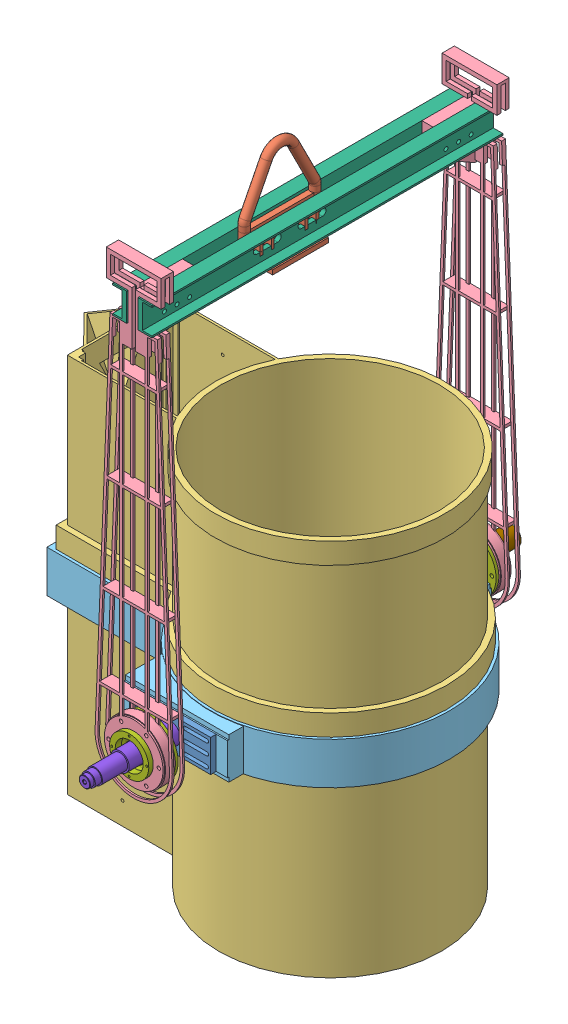
SolidWorks assembly MAIN ASSEMBLY, configuration Default. Lengths in mm.
Overall size (1306.1 2334 1530).
13 component instances, 9 part files, 32 mates.
Components (placement in the parent):
- END BRACKET ON TRUNNION SHAFT - GEAR END & OFF END-1: END BRACKET ON TRUNNION SHAFT - GEAR END & OFF END [Default] at (1445.5704 513.2068 -637.5435) x (1 0 0) z (0 -1 0) size (290 20 115)
- HOOK-1: HOOK [Default] at (1445.5704 1896.7068 -44.8635) x (0 0 -1) z (1 0 0) size (284 342 150)
- SHEEL-1: SHEEL [Default] at (1525.5704 -170.7932 -145.5435) size (1297.1 1360 836)
- SIDE BAILARM-1: SIDE BAILARM [Default] at (1445.5704 513.2068 -745.5435) size (276 1657 194)
- T.RING WITH BRACKETS-1: T.RING WITH BRACKETS [Default] at (1525.5704 438.2068 -145.5435) x (-1 0 0) z (0 0 -1) size (1226.08 150 944)
- TOP BAILARM-1: TOP BAILARM [Default] at (1417.5704 1887.2068 -772.5435) x (0 0 1) z (-1 0 0) size (1254 100 50)
- TRUNNION HOUSING - GEAR END, OFF END - FINISHING-1: TRUNNION HOUSING - GEAR END, OFF END - FINISHING [Default] at (1445.5704 513.2068 417.4565) x (1 0.000054 0) z (0.000054 -1 0) size (210 75 210)
- TRUNNION SHAFT - GEAR END-1: TRUNNION SHAFT - GEAR END [Default] at (1445.5704 513.2068 329.4565) x (0 0 1) z (0.352968 0.935635 0) size (323 75 75)
- TRUNNION SHAFT - OFF END-1: TRUNNION SHAFT - OFF END [Default] at (1445.5704 513.2068 -620.5435) x (0 0 -1) z (1 0 0) size (257 75 75)
- SIDE BAILARM-2: SIDE BAILARM [Default] at (1445.5704 513.2068 454.4565) x (-1 0 0) z (0 0 -1) size (276 1657 194)
- END BRACKET ON TRUNNION SHAFT - GEAR END & OFF END-2: END BRACKET ON TRUNNION SHAFT - GEAR END & OFF END [Default] at (1445.5704 513.2068 346.4565) x (-1 0 0) z (0 -1 0) size (290 20 115)
- TRUNNION HOUSING - GEAR END, OFF END - FINISHING-2: TRUNNION HOUSING - GEAR END, OFF END - FINISHING [Default] at (1445.5704 513.2068 -708.5435) x (1 0 0) z (0 1 0) size (210 75 210)
- TOP BAILARM-2: TOP BAILARM [Default] at (1473.5704 1887.2068 -772.5435) x (0 0 1) z (1 0 0) size (1254 100 50)
Mates (geometry in assembly coordinates):
- Concentric1: concentric aligned: cylinder of SHEEL-1 through (1525.5704 1189.2068 -145.5435) axis (0 -1 0) radius 398; cylinder of T.RING WITH BRACKETS-1 through (1525.5704 588.2068 -145.5435) axis (0 -1 0) radius 402
- Coincident1: coincident anti-aligned: plane of SHEEL-1 through (1525.5704 588.2068 -145.5435) normal (0 -1 0); plane of T.RING WITH BRACKETS-1 through (1525.5704 588.2068 -145.5435) normal (0 1 0)
- Coincident2: coincident anti-aligned: plane of END BRACKET ON TRUNNION SHAFT - GEAR END & OFF END-1 through (1445.5704 513.2068 -637.5435) normal (0 0 -1); plane of TRUNNION SHAFT - OFF END-1 through (1445.5704 527.9068 -637.5435) normal (0 0 1)
- Concentric2: concentric aligned: cylinder of END BRACKET ON TRUNNION SHAFT - GEAR END & OFF END-1 through (1445.5704 513.2068 -637.5435) axis (0 0 1) radius 14.75; cylinder of TRUNNION SHAFT - OFF END-1 through (1445.5704 513.2068 -620.5435) axis (0 0 1) radius 14.7
- Coincident3: coincident anti-aligned: plane of TRUNNION SHAFT - GEAR END-1 through (1459.3242 508.0182 346.4565) normal (0 0 -1); plane of END BRACKET ON TRUNNION SHAFT - GEAR END & OFF END-2 through (1445.5704 513.2068 346.4565) normal (0 0 1)
- Concentric3: concentric aligned: cylinder of TRUNNION SHAFT - GEAR END-1 through (1445.5704 513.2068 329.4565) axis (0 0 -1) radius 14.7; cylinder of END BRACKET ON TRUNNION SHAFT - GEAR END & OFF END-2 through (1445.5704 513.2068 346.4565) axis (0 0 -1) radius 14.75
- Coincident4: coincident anti-aligned: plane of END BRACKET ON TRUNNION SHAFT - GEAR END & OFF END-1 through (1445.5704 513.2068 -617.5435) normal (0 0 1); plane of T.RING WITH BRACKETS-1 through (1525.5704 438.2068 -617.5435) normal (0 0 -1)
- Coincident6: coincident aligned: plane of END BRACKET ON TRUNNION SHAFT - GEAR END & OFF END-1 through (1300.5704 570.7068 -617.5435) normal (0 1 0); plane of T.RING WITH BRACKETS-1 through (1630.5704 570.7068 -617.5435) normal (0 1 0)
- Width1: width anti-aligned: plane of T.RING WITH BRACKETS-1 through (1630.5704 439.7068 -612.5435) normal (1 0 0); plane of END BRACKET ON TRUNNION SHAFT - GEAR END & OFF END-1 through (1260.5704 439.7068 -612.5435) normal (-1 0 0); plane of T.RING WITH BRACKETS-1 through (1300.5704 455.7068 -617.5435) normal (-1 0 0); plane of END BRACKET ON TRUNNION SHAFT - GEAR END & OFF END-1 through (1590.5704 455.7068 -617.5435) normal (1 0 0)
- Coincident9: coincident anti-aligned: plane of SIDE BAILARM-1 through (1445.5704 513.2068 -723.5435) normal (0 0 1); plane of TRUNNION HOUSING - GEAR END, OFF END - FINISHING-2 through (1445.5704 513.2068 -723.5435) normal (0 0 -1)
- Concentric6: concentric aligned: cylinder of SIDE BAILARM-1 through (1445.5704 513.2068 -767.5435) axis (0 0 1) radius 70; cylinder of TRUNNION HOUSING - GEAR END, OFF END - FINISHING-2 through (1445.5704 513.2068 -783.5445) axis (0 0 1) radius 50
- Concentric7: concentric anti-aligned: cylinder of SIDE BAILARM-1 through (1535.5704 513.2068 -723.5435) axis (0 0 1) radius 6.25; cylinder of TRUNNION HOUSING - GEAR END, OFF END - FINISHING-2 through (1535.5704 513.2068 -723.5435) axis (0 0 -1) radius 6.5
- Concentric8: concentric aligned: cylinder of TRUNNION SHAFT - OFF END-1 through (1445.5704 513.2068 -620.5435) axis (0 0 1) radius 37.5; cylinder of TRUNNION HOUSING - GEAR END, OFF END - FINISHING-2 through (1445.5704 513.2068 -741.0435) axis (0 0 1) radius 55.4
- Width2: width aligned: plane of T.RING WITH BRACKETS-1 through (1630.5704 439.7068 -612.5435) normal (1 0 0); plane of SIDE BAILARM-1 through (1260.5704 439.7068 -612.5435) normal (-1 0 0); plane of T.RING WITH BRACKETS-1 through (1465.5704 513.2068 -745.5435) normal (1 0 0); plane of SIDE BAILARM-1 through (1425.5704 513.2068 -745.5435) normal (-1 0 0)
- Coincident10: coincident anti-aligned: plane of TRUNNION HOUSING - GEAR END, OFF END - FINISHING-1 through (1445.5704 513.2068 432.4565) normal (0 0 1); plane of SIDE BAILARM-2 through (1445.5704 513.2068 432.4565) normal (0 0 -1)
- Concentric9: concentric aligned: cylinder of TRUNNION HOUSING - GEAR END, OFF END - FINISHING-1 through (1445.5704 513.2068 492.4575) axis (0 0 -1) radius 70; cylinder of SIDE BAILARM-2 through (1445.5704 513.2068 476.4565) axis (0 0 -1) radius 70
- Coincident11: coincident anti-aligned: plane of T.RING WITH BRACKETS-1 through (1525.5704 438.2068 326.4565) normal (0 0 1); plane of END BRACKET ON TRUNNION SHAFT - GEAR END & OFF END-2 through (1445.5704 513.2068 326.4565) normal (0 0 -1)
- Coincident13: coincident aligned: plane of T.RING WITH BRACKETS-1 through (1630.5704 570.7068 326.4565) normal (0 1 0); plane of END BRACKET ON TRUNNION SHAFT - GEAR END & OFF END-2 through (1590.5704 570.7068 326.4565) normal (0 1 0)
- Width3: width anti-aligned: plane of T.RING WITH BRACKETS-1 through (1260.5704 439.7068 321.4565) normal (-1 0 0); plane of END BRACKET ON TRUNNION SHAFT - GEAR END & OFF END-2 through (1630.5704 439.7068 321.4565) normal (1 0 0); plane of T.RING WITH BRACKETS-1 through (1590.5704 455.7068 326.4565) normal (1 0 0); plane of END BRACKET ON TRUNNION SHAFT - GEAR END & OFF END-2 through (1300.5704 455.7068 326.4565) normal (-1 0 0)
- Concentric11: concentric aligned: cylinder of TRUNNION HOUSING - GEAR END, OFF END - FINISHING-1 through (1445.5704 513.2068 449.9565) axis (0 0 -1) radius 55.4; cylinder of TRUNNION SHAFT - GEAR END-1 through (1445.5704 513.2068 329.4565) axis (0 0 -1) radius 27.5
- Width4: width anti-aligned: plane of T.RING WITH BRACKETS-1 through (1260.5704 439.7068 321.4565) normal (-1 0 0); plane of SIDE BAILARM-2 through (1630.5704 439.7068 321.4565) normal (1 0 0); plane of T.RING WITH BRACKETS-1 through (1465.5704 513.2068 454.4565) normal (1 0 0); plane of SIDE BAILARM-2 through (1425.5704 513.2068 454.4565) normal (-1 0 0)
- Coincident15: coincident anti-aligned: plane of TOP BAILARM-1 through (1425.5704 1887.2068 481.4565) normal (1 0 0); plane of SIDE BAILARM-2 through (1425.5704 513.2068 454.4565) normal (-1 0 0)
- Concentric12: concentric aligned: cylinder of TOP BAILARM-1 through (1409.5704 1912.2068 402.4565) axis (-1 0 0) radius 7; cylinder of SIDE BAILARM-2 through (1425.5704 1912.2068 402.4565) axis (-1 0 0) radius 7
- Concentric13: concentric anti-aligned: cylinder of SIDE BAILARM-1 through (1465.5704 1912.2068 -693.5435) axis (1 0 0) radius 7; cylinder of TOP BAILARM-1 through (1409.5704 1912.2068 -693.5435) axis (-1 0 0) radius 7
- Width5: width anti-aligned: plane of T.RING WITH BRACKETS-1 through (1525.5704 438.2068 -617.5435) normal (0 0 -1); plane of SIDE BAILARM-2 through (1525.5704 438.2068 326.4565) normal (0 0 1); plane of T.RING WITH BRACKETS-1 through (1445.5704 513.2068 476.4565) normal (0 0 1); plane of SIDE BAILARM-1 through (1445.5704 513.2068 -767.5435) normal (0 0 -1)
- Coincident16: coincident anti-aligned: plane of SIDE BAILARM-2 through (1465.5704 513.2068 454.4565) normal (1 0 0); plane of TOP BAILARM-2 through (1465.5704 1887.2068 481.4565) normal (-1 0 0)
- Concentric14: concentric anti-aligned: cylinder of SIDE BAILARM-2 through (1425.5704 1912.2068 402.4565) axis (-1 0 0) radius 7; cylinder of TOP BAILARM-2 through (1481.5704 1912.2068 402.4565) axis (1 0 0) radius 7
- Concentric15: concentric aligned: cylinder of SIDE BAILARM-1 through (1465.5704 1912.2068 -693.5435) axis (1 0 0) radius 7; cylinder of TOP BAILARM-2 through (1481.5704 1912.2068 -693.5435) axis (1 0 0) radius 7
- Width6: width aligned: plane of HOOK-1 through (1455.5704 1837.2068 -186.8645) normal (1 0 0); plane of TOP BAILARM-1 through (1435.5704 1937.2068 97.1375) normal (-1 0 0); plane of HOOK-1 through (1425.5704 1887.2068 481.4565) normal (1 0 0); plane of TOP BAILARM-2 through (1465.5704 1887.2068 481.4565) normal (-1 0 0)
- Concentric16: concentric aligned: line of HOOK-1 through (1429.5704 1887.2068 35.1365) axis (1 0 0); axis of TOP BAILARM-2 through (1465.5704 1887.2068 35.1365) axis (1 0 0)
- Concentric17: concentric anti-aligned: cylinder of HOOK-1 through (1429.5704 1887.2068 -124.8635) axis (1 0 0) radius 12.5; line of TOP BAILARM-1 through (1425.5704 1887.2068 -124.8635) axis (-1 0 0)
- Width7: width anti-aligned: plane of T.RING WITH BRACKETS-1 through (1525.5704 588.2068 42.4565) normal (0 0 -1); plane of SHEEL-1 through (1525.5704 588.2068 -333.5435) normal (0 0 1); plane of T.RING WITH BRACKETS-1 through (769.5704 -170.7932 37.4565) normal (0 0 1); plane of SHEEL-1 through (769.5704 -170.7932 -328.5435) normal (0 0 -1)
